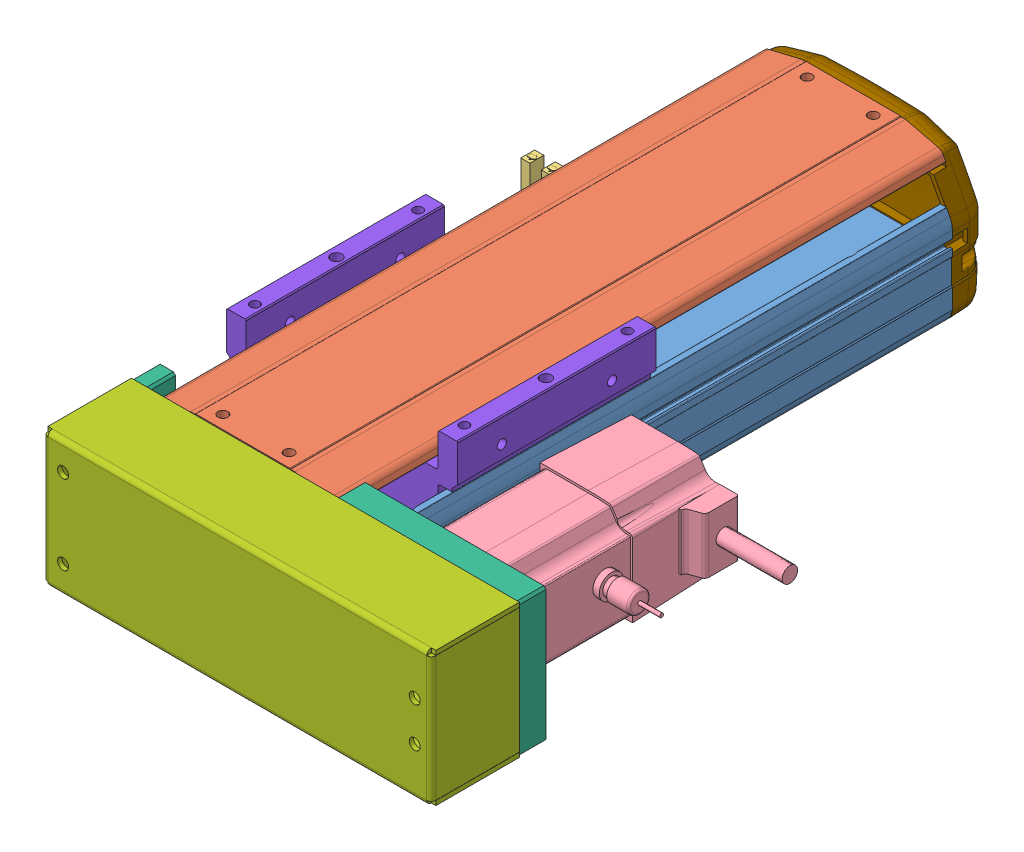
SolidWorks assembly S10-BL-100W, configuration 默认. Lengths in mm.
Overall size (211 67.16 332.24).
11 component instances, 9 part files, 39 mates.
Components (placement in the parent):
- S10-BR底座^S10-BL-100W-1: S10-BR底座^S10-BL-100W [默认] at (-105.9271 -5.9237 -417.9615) size (102 43 271) (virtual)
- S10-BR上盖^S10-BL-100W-1: S10-BR上盖^S10-BL-100W [默认] at (-105.9271 53.5763 -273.4615) size (83.88 8 277) (virtual)
- EE-SX672 传感器^S10-BL-100W-1: EE-SX672 传感器^S10-BL-100W [默认] at (-163.6771 28.1763 -331.8615) x (-1 0 0) z (0 0 1) size (13.5 27.4 26.1) (virtual)
- M10^S10-BL-100W-1: M10^S10-BL-100W [默认] at (-18.1271 25.5763 -202.9615) x (0 -1 0) z (0 0 -1) size (42.1 79.78 121.76) (virtual)
- S10-GY外置感应钢片^S10-BL-100W-1: S10-GY外置感应钢片^S10-BL-100W [默认] at (-158.8271 54.5763 -224.9615) x (-1 0 0) z (0 0 -1) size (6 19 61) (virtual)
- EE-SX672 传感器^S10-BL-100W-2: EE-SX672 传感器^S10-BL-100W [默认] at (-163.6771 28.1763 -241.1615) x (-1 0 0) z (0 0 1) size (13.5 27.4 26.1) (virtual)
- EE-SX672 传感器^S10-BL-100W-3: EE-SX672 传感器^S10-BL-100W [默认] at (-163.6771 28.1763 -215.0615) x (-1 0 0) z (0 0 1) size (13.5 27.4 26.1) (virtual)
- S10-BL-P10电机左折板^S10-BL-100W-1: S10-BL-P10电机左折板^S10-BL-100W [Default] at (1022.9077 -789.214 -140.9615) x (-1 0 0) z (0 -1 0) size (176 12 61) (virtual)
- S10-BL盖子^S10-BL-100W-1: S10-BL盖子^S10-BL-100W [默认] at (-154.4271 -5.9237 -94.9615) size (176 61.01 40.01) (virtual)
- S10-BC滑座^S10-BL-100W-1: S10-BC滑座^S10-BL-100W [默认] at (-87.4271 24.5763 -224.9615) x (-1 0 0) z (0 0 -1) size (105 52.5 90) (virtual)
- 复件 S10端盖^S10-BL-100W-2: 复件 S10端盖^S10-BL-100W [Default] at (-105.8271 -7.4742 14.1385) size (104.96 63.3 21.34) (virtual)
Mates (geometry in assembly coordinates):
- 距离2: distance = 62.5 mm: plane of S10-BR上盖^S10-BL-100W-1 through (-127.2363 55.5763 -134.9615) normal (0 1 0); plane of S10-BR底座^S10-BL-100W-1 through (-105.9271 -6.9237 -417.9615) normal (0 -1 0)
- 重合31: coincident: plane of S10-BR底座^S10-BL-100W-1 through (-105.9271 -5.9237 -417.9615) normal (1 0 0); plane of S10-BR上盖^S10-BL-100W-1 through (-105.9271 53.5763 -273.4615) normal (1 0 0)
- 距离3: distance = 66 mm: plane of S10-BC滑座^S10-BL-100W-1 through (-35.7874 59.0763 -154.2043) normal (0 1 0); plane of S10-BR底座^S10-BL-100W-1 through (-105.9271 -6.9237 -417.9615) normal (0 -1 0)
- 距离5: distance = 1.5 mm: plane of S10-BC滑座^S10-BL-100W-1 through (-158.4271 39.1592 -269.9615) normal (-1 0 0); plane of S10-BR底座^S10-BL-100W-1 through (-156.9271 5.993 -146.9615) normal (-1 0 0)
- 距离8: distance = 24 mm: plane of S10-BR底座^S10-BL-100W-1 through (-105.9271 -6.9237 -417.9615) normal (0 -1 0); plane of EE-SX672 传感器^S10-BL-100W-1 through (-156.9271 17.0763 -325.5615) normal (0 -1 0)
- 重合84: coincident: plane of S10-BR底座^S10-BL-100W-1 through (-156.9271 28.5896 -146.9615) normal (-1 0 0); plane of EE-SX672 传感器^S10-BL-100W-1 through (-156.9271 39.2763 -325.5615) normal (1 0 0)
- 重合43: coincident: plane of S10-BC滑座^S10-BL-100W-1 through (-158.4271 39.1592 -269.9615) normal (-1 0 0); plane of S10-GY外置感应钢片^S10-BL-100W-1 through (-158.4271 52.5763 -194.4615) normal (1 0 0)
- 同心16: concentric: cylinder of S10-BC滑座^S10-BL-100W-1 through (-158.4271 48.0763 -246.1615) axis (-1 0 0) radius 2.1; cylinder of S10-GY外置感应钢片^S10-BL-100W-1 through (-158.4271 48.0763 -246.1615) axis (1 0 0) radius 2.8
- 同心17: concentric: cylinder of S10-BC滑座^S10-BL-100W-1 through (-158.4271 48.0763 -196.1615) axis (-1 0 0) radius 2.1; cylinder of S10-GY外置感应钢片^S10-BL-100W-1 through (-158.4271 48.0763 -196.1615) axis (1 0 0) radius 2.8
- 重合56: coincident: plane of S10-BR底座^S10-BL-100W-1 through (-151.5313 35.8763 -146.9615) normal (0 0 1); plane of S10-BL-P10电机左折板^S10-BL-100W-1 through (1022.9077 -789.214 -146.9615) normal (0 0 -1)
- 重合57: coincident: plane of S10-BR底座^S10-BL-100W-1 through (-130.4272 -5.9237 -146.9615) normal (0 -1 0); plane of S10-BL-P10电机左折板^S10-BL-100W-1 through (-142.9886 -5.9237 -146.9615) normal (0 -1 0)
- 重合58: coincident: plane of S10-BR底座^S10-BL-100W-1 through (-156.4271 17.493 -146.9615) normal (-1 0 0); plane of S10-BL-P10电机左折板^S10-BL-100W-1 through (-156.4271 32.818 -146.9615) normal (-1 0 0)
- 重合61: coincident: plane of S10-BL-P10电机左折板^S10-BL-100W-1 through (19.5729 54.0763 -146.9615) normal (1 0 0); plane of S10-BL盖子^S10-BL-100W-1 through (19.5729 -3.8237 -96.9615) normal (1 0 0)
- 重合62: coincident: plane of S10-BL-P10电机左折板^S10-BL-100W-1 through (1022.9077 -789.214 -134.9615) normal (0 0 1); plane of S10-BL盖子^S10-BL-100W-1 through (-154.4271 -5.9237 -134.9615) normal (0 0 -1)
- 重合63: coincident: plane of S10-BL-P10电机左折板^S10-BL-100W-1 through (-62.4271 55.0763 -146.9615) normal (0 1 0); plane of S10-BL盖子^S10-BL-100W-1 through (17.5729 55.0763 -96.9615) normal (0 1 0)
- 重合64: coincident: plane of S10-BL-P10电机左折板^S10-BL-100W-1 through (1022.9077 -789.214 -146.9615) normal (0 0 -1); plane of M10^S10-BL-100W-1 through (-16.6293 -52.4221 -146.9615) normal (0 0 1)
- 重合66: coincident: plane of S10-BL-P10电机左折板^S10-BL-100W-1 through (1022.9077 -789.214 -146.9615) normal (0 0 -1); plane of M10^S10-BL-100W-1 through (-16.6293 -52.4221 -146.9615) normal (0 0 1)
- 平行2: parallel: plane of S10-BL-P10电机左折板^S10-BL-100W-1 through (19.5729 54.0763 -146.9615) normal (1 0 0); plane of M10^S10-BL-100W-1 through (1.8729 25.5763 -202.9615) normal (1 0 0)
- 距离12: distance = 74 mm: plane of EE-SX672 传感器^S10-BL-100W-1 through (-170.4271 17.0763 -331.8615) normal (0 0 -1); plane of S10-BR底座^S10-BL-100W-1 through (-163.5031 36.0763 -405.8615) normal (0 0 -1)
- 重合77: coincident: plane of EE-SX672 传感器^S10-BL-100W-1 through (-156.9271 39.2763 -325.5615) normal (0 1 0); plane of EE-SX672 传感器^S10-BL-100W-2 through (-156.9271 39.2763 -234.8615) normal (0 1 0)
- 重合78: coincident: plane of EE-SX672 传感器^S10-BL-100W-1 through (-170.4271 39.2763 -325.5615) normal (-1 0 0); plane of EE-SX672 传感器^S10-BL-100W-2 through (-170.4271 39.2763 -234.8615) normal (-1 0 0)
- 重合79: coincident: plane of EE-SX672 传感器^S10-BL-100W-2 through (-170.4271 39.2763 -234.8615) normal (-1 0 0); plane of EE-SX672 传感器^S10-BL-100W-3 through (-170.4271 39.2763 -208.7615) normal (-1 0 0)
- 重合80: coincident: plane of EE-SX672 传感器^S10-BL-100W-1 through (-156.9271 39.2763 -325.5615) normal (0 1 0); plane of EE-SX672 传感器^S10-BL-100W-3 through (-156.9271 39.2763 -208.7615) normal (0 1 0)
- 距离13: distance = 58 mm: plane of S10-BR底座^S10-BL-100W-1 through (-151.5313 35.8763 -146.9615) normal (0 0 1); plane of EE-SX672 传感器^S10-BL-100W-3 through (-170.4271 17.0763 -208.7615) normal (0 0 1)
- 重合81: coincident: plane of EE-SX672 传感器^S10-BL-100W-2 through (-156.9271 39.2763 -234.8615) normal (1 0 0); plane of EE-SX672 传感器^S10-BL-100W-3 through (-156.9271 39.2763 -208.7615) normal (1 0 0)
- 重合82: coincident: plane of EE-SX672 传感器^S10-BL-100W-1 through (-156.9271 39.2763 -325.5615) normal (1 0 0); plane of EE-SX672 传感器^S10-BL-100W-2 through (-156.9271 39.2763 -234.8615) normal (1 0 0)
- 重合83: coincident: plane of EE-SX672 传感器^S10-BL-100W-2 through (-159.9271 20.2763 -224.9615) normal (0 0 1); plane of EE-SX672 传感器^S10-BL-100W-3 through (-159.9271 20.2763 -224.9615) normal (0 0 -1)
- 重合85: coincident: plane of S10-BR底座^S10-BL-100W-1 through (-59.1771 36.0763 -405.8615) normal (0 0 -1); plane of 复件 S10端盖^S10-BL-100W-2 through (-149.0117 28.5258 -405.8615) normal (0 0 1)
- 重合87: coincident: line of S10-BR底座^S10-BL-100W-1 through (-58.8271 20.5258 -405.8615) axis (0 1 0); line of 复件 S10端盖^S10-BL-100W-2 through (-58.8271 25.9258 -405.8615) axis (0 -1 0)
- 重合88: coincident: line of S10-BR底座^S10-BL-100W-1 through (-58.5271 25.9258 -405.8615) axis (1 0 0); line of 复件 S10端盖^S10-BL-100W-2 through (-54.8271 25.9258 -405.8615) axis (-1 0 0)
- 重合90: coincident: plane of S10-BR上盖^S10-BL-100W-1 through (-145.8568 47.7763 -134.9615) normal (0 0 1); plane of S10-BL盖子^S10-BL-100W-1 through (17.5729 55.0763 -134.9615) normal (0 0 -1)
- 宽度1: width: plane of EE-SX672 传感器^S10-BL-100W-2 through (-170.4271 17.0763 -231.0615) normal (0 0 1); plane of EE-SX672 传感器^S10-BL-100W-3 through (-170.4271 17.0763 -211.2615) normal (0 0 -1); plane of S10-GY外置感应钢片^S10-BL-100W-1 through (-159.2271 43.5763 -228.6615) normal (0 0 -1); plane of S10-GY外置感应钢片^S10-BL-100W-1 through (-159.2271 43.5763 -213.6615) normal (0 0 1)
- 距离15: distance = 32.5 mm: cylinder of M10^S10-BL-100W-1 through (-18.1271 25.5763 -121.9615) axis (0 0 -1) radius 4; plane of S10-BR底座^S10-BL-100W-1 through (-105.9271 -6.9237 -417.9615) normal (0 -1 0)
- 距离16: distance = 36.8 mm: cylinder of M10^S10-BL-100W-1 through (-18.1271 25.5763 -121.9615) axis (0 0 -1) radius 4; plane of S10-BR底座^S10-BL-100W-1 through (-54.9271 -2.8683 -146.9615) normal (1 0 0)
- 距离17: distance = 130 mm: plane of S10-BL盖子^S10-BL-100W-1 through (17.5729 55.0763 -94.9615) normal (0 0 1); cylinder of S10-BC滑座^S10-BL-100W-1 through (-153.4271 47.0763 -224.9615) axis (0 1 0) radius 2.5
- 同心18: concentric: cylinder of S10-GY外置感应钢片^S10-BL-100W-1 through (-158.4271 48.0763 -249.9615) axis (1 0 0) radius 2.8; cylinder of S10-BC滑座^S10-BL-100W-1 through (-158.4271 48.0763 -249.9615) axis (-1 0 0) radius 2.1
- 同心19: concentric: cylinder of S10-GY外置感应钢片^S10-BL-100W-1 through (-158.4271 48.0763 -199.9615) axis (1 0 0) radius 2.8; cylinder of S10-BC滑座^S10-BL-100W-1 through (-158.4271 48.0763 -199.9615) axis (-1 0 0) radius 2.1
- 宽度2: width: plane of EE-SX672 传感器^S10-BL-100W-2 through (-170.4271 17.0763 -234.8615) normal (0 0 1); plane of EE-SX672 传感器^S10-BL-100W-3 through (-170.4271 17.0763 -215.0615) normal (0 0 -1); plane of S10-GY外置感应钢片^S10-BL-100W-1 through (-159.2271 43.5763 -217.4615) normal (0 0 1); plane of S10-GY外置感应钢片^S10-BL-100W-1 through (-159.2271 43.5763 -232.4615) normal (0 0 -1)
- 距离18: distance = 66 mm: plane of S10-BC滑座^S10-BL-100W-1 through (-35.7874 59.0763 -154.2043) normal (0 1 0); plane of S10-BR底座^S10-BL-100W-1 through (-105.9271 -6.9237 -417.9615) normal (0 -1 0)
